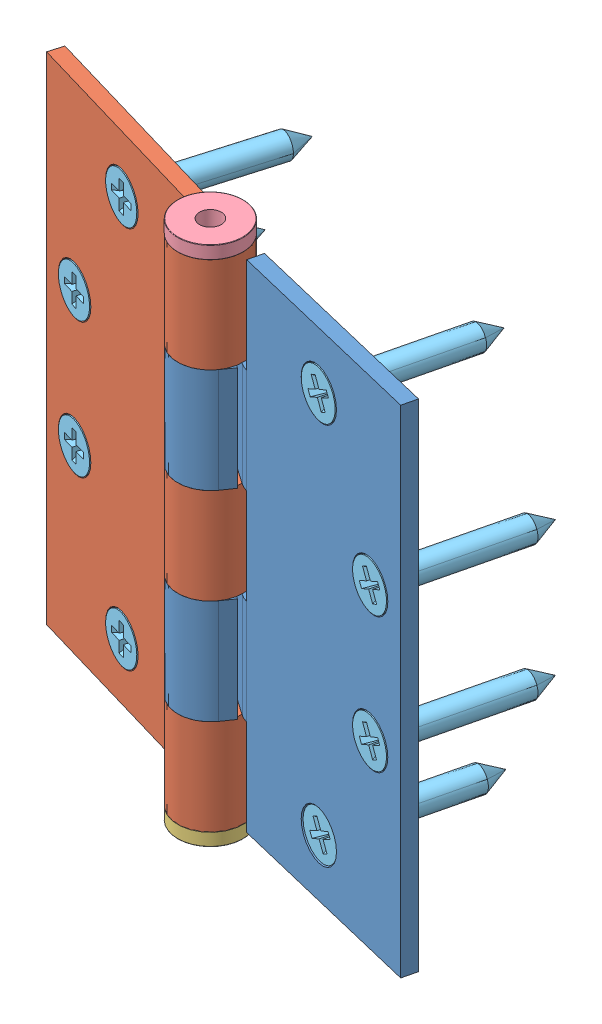
SolidWorks assembly socket pintu, configuration Default. Lengths in mm.
Overall size (119.47 119.8 70.68).
12 component instances, 5 part files, 46 mates.
Components (placement in the parent):
- Door Leaf-1: Door Leaf [Default] at (364.6395 -1637.4416 -365.5587) x (-0.972076 0 -0.234664) z (-0.234664 0 0.972076) size (65 114 15)
- Door right-3: Door right [Default] at (300.0571 -1637.4416 -382.8054) x (-0.959648 0 -0.281202) z (-0.281202 0 0.959648) size (65 114 15)
- Pin, Ball Bearing Door Hinge-1: Pin, Ball Bearing Door Hinge [Default] at (331.4179 -1694.3416 -370.6981) x (-1 0 0) z (0 0 1) size (15 110 15)
- Bottom Pin, Ball Bearing Door Hinge-1: Bottom Pin, Ball Bearing Door Hinge [Default] at (331.4179 -1577.5416 -370.6981) x (0.868974 0 -0.494857) z (-0.494857 0 -0.868974) size (15 9.5 15)
- M5.5 x 30, Wood Screw, Ball Bearing Door Hinge-1: M5.5 x 30, Wood Screw, Ball Bearing Door Hinge [Default] at (363.6317 -1681.4416 -367.7758) x (0.234664 0 -0.972076) z (0.849541 0.486025 0.205084) size (35.4 10.56 10.56)
- M5.5 x 30, Wood Screw, Ball Bearing Door Hinge-2: M5.5 x 30, Wood Screw, Ball Bearing Door Hinge [Default] at (286.5861 -1621.9416 -388.3979) x (0.281202 0 -0.959648) z (0.959648 0.000088 0.281202) size (35.4 10.56 10.56)
- M5.5 x 30, Wood Screw, Ball Bearing Door Hinge-3: M5.5 x 30, Wood Screw, Ball Bearing Door Hinge [Default] at (286.5861 -1652.9416 -388.3979) x (0.281202 0 -0.959648) z (0.959648 0.000088 0.281202) size (35.4 10.56 10.56)
- M5.5 x 30, Wood Screw, Ball Bearing Door Hinge-4: M5.5 x 30, Wood Screw, Ball Bearing Door Hinge [Default] at (301.9405 -1593.4416 -383.8986) x (0.281202 0 -0.959648) z (0.959648 0.000088 0.281202) size (35.4 10.56 10.56)
- M5.5 x 30, Wood Screw, Ball Bearing Door Hinge-5: M5.5 x 30, Wood Screw, Ball Bearing Door Hinge [Default] at (301.9405 -1681.4416 -383.8986) x (0.281202 0 -0.959648) z (0.959648 0.000088 0.281202) size (35.4 10.56 10.56)
- M5.5 x 30, Wood Screw, Ball Bearing Door Hinge-10: M5.5 x 30, Wood Screw, Ball Bearing Door Hinge [Default] at (379.1051 -1652.9416 -363.6907) x (0.234664 0 -0.972076) z (0.849541 0.486025 0.205084) size (35.4 10.56 10.56)
- M5.5 x 30, Wood Screw, Ball Bearing Door Hinge-11: M5.5 x 30, Wood Screw, Ball Bearing Door Hinge [Default] at (379.1051 -1621.9416 -363.6907) x (0.234664 0 -0.972076) z (0.849541 0.486025 0.205084) size (35.4 10.56 10.56)
- M5.5 x 30, Wood Screw, Ball Bearing Door Hinge-12: M5.5 x 30, Wood Screw, Ball Bearing Door Hinge [Default] at (363.5519 -1593.4416 -367.4453) x (0.234664 0 -0.972076) z (0.849541 0.486025 0.205084) size (35.4 10.56 10.56)
Mates (geometry in assembly coordinates):
- Concentric1: concentric anti-aligned: circle of Door Frame Leaf, Ball Bearing Door Hinge-3; circle of Pin, Ball Bearing Door Hinge-1
- Coincident1: coincident anti-aligned: circle of Door Frame Leaf, Ball Bearing Door Hinge-3; circle of Pin, Ball Bearing Door Hinge-1
- Coincident2: coincident aligned: circle of Door Leaf, Ball Bearing Door Hinge-1; circle of Door Frame Leaf, Ball Bearing Door Hinge-3
- Concentric4: concentric anti-aligned: circle of Door Frame Leaf, Ball Bearing Door Hinge-3; circle of Bottom Pin, Ball Bearing Door Hinge-1
- Coincident3: coincident aligned: circle of Door Frame Leaf, Ball Bearing Door Hinge-3; circle of Bottom Pin, Ball Bearing Door Hinge-1
- Concentric6: concentric aligned: circle of Door Leaf, Ball Bearing Door Hinge-1; circle of M5.5 x 30, Wood Screw, Ball Bearing Door Hinge-1
- Coincident4: coincident aligned: cone of Door Leaf, Ball Bearing Door Hinge-1 through (363.111 -1681.4416 -365.619) axis (0.234664 0 -0.972076); circle of M5.5 x 30, Wood Screw, Ball Bearing Door Hinge-1
- Coincident6: coincident aligned: cone of Door Frame Leaf, Ball Bearing Door Hinge-3 through (301.4122 -1681.4416 -382.0957) axis (0.281202 0 -0.959648); circle of M5.5 x 30, Wood Screw, Ball Bearing Door Hinge-5
- Coincident7: coincident aligned: cone of Door Frame Leaf, Ball Bearing Door Hinge-3 through (286.0578 -1652.9416 -386.5949) axis (0.281202 0 -0.959648); circle of M5.5 x 30, Wood Screw, Ball Bearing Door Hinge-3
- Coincident8: coincident aligned: cone of Door Frame Leaf, Ball Bearing Door Hinge-3 through (286.0578 -1621.9416 -386.5949) axis (0.281202 0 -0.959648); circle of M5.5 x 30, Wood Screw, Ball Bearing Door Hinge-2
- Coincident9: coincident aligned: cone of Door Frame Leaf, Ball Bearing Door Hinge-3 through (301.4122 -1593.4416 -382.0957) axis (0.281202 0 -0.959648); circle of M5.5 x 30, Wood Screw, Ball Bearing Door Hinge-4
- Coincident10: coincident aligned: cone of Door Leaf, Ball Bearing Door Hinge-1 through (378.6642 -1652.9416 -361.8644) axis (0.234664 0 -0.972076); circle of M5.5 x 30, Wood Screw, Ball Bearing Door Hinge-10
- Coincident11: coincident aligned: cone of Door Leaf, Ball Bearing Door Hinge-1 through (378.6642 -1621.9416 -361.8644) axis (0.234664 0 -0.972076); circle of M5.5 x 30, Wood Screw, Ball Bearing Door Hinge-11
- Coincident12: coincident aligned: cone of Door Leaf, Ball Bearing Door Hinge-1 through (363.111 -1593.4416 -365.619) axis (0.234664 0 -0.972076); circle of M5.5 x 30, Wood Screw, Ball Bearing Door Hinge-12
- Coincident13: coincident anti-aligned: circle of Pin, Ball Bearing Door Hinge-2; circle of Door Frame Leaf, Ball Bearing Door Hinge-4
- Concentric7: concentric anti-aligned: cylinder of Door Leaf, Ball Bearing Door Hinge-2; cylinder of Pin, Ball Bearing Door Hinge-2 through (331.4179 495.6584 -370.6981) axis (0 -1 0) radius 4
- Coincident14: coincident aligned: circle of Door Leaf, Ball Bearing Door Hinge-2; circle of Door Frame Leaf, Ball Bearing Door Hinge-4
- Coincident15: coincident aligned: cone of Door Frame Leaf, Ball Bearing Door Hinge-4 through (286.0578 464.0584 -386.5949) axis (0.281202 0 -0.959648); circle of M5.5 x 30, Wood Screw, Ball Bearing Door Hinge-20
- Coincident16: coincident aligned: circle of M5.5 x 30, Wood Screw, Ball Bearing Door Hinge-13; cone of Door Frame Leaf, Ball Bearing Door Hinge-4 through (286.0578 433.0584 -386.5949) axis (0.281202 0 -0.959648)
- Coincident17: coincident aligned: cone of Door Frame Leaf, Ball Bearing Door Hinge-4 through (301.4122 404.5584 -382.0957) axis (0.281202 0 -0.959648); circle of M5.5 x 30, Wood Screw, Ball Bearing Door Hinge-14
- Coincident18: coincident aligned: cone of Door Leaf, Ball Bearing Door Hinge-2 through (363.111 404.5584 -365.619) axis (0.234664 0 -0.972076); circle of M5.5 x 30, Wood Screw, Ball Bearing Door Hinge-18
- Coincident19: coincident aligned: cone of Door Leaf, Ball Bearing Door Hinge-2 through (378.6642 433.0584 -361.8644) axis (0.234664 0 -0.972076); circle of M5.5 x 30, Wood Screw, Ball Bearing Door Hinge-16
- Coincident20: coincident aligned: cone of Door Leaf, Ball Bearing Door Hinge-2 through (378.6642 464.0584 -361.8644) axis (0.234664 0 -0.972076); circle of M5.5 x 30, Wood Screw, Ball Bearing Door Hinge-15
- Coincident21: coincident aligned: cone of Door Leaf, Ball Bearing Door Hinge-2 through (363.111 492.5584 -365.619) axis (0.234664 0 -0.972076); circle of M5.5 x 30, Wood Screw, Ball Bearing Door Hinge-17
- Coincident22: coincident aligned: cone of Door Frame Leaf, Ball Bearing Door Hinge-4 through (301.4122 492.5584 -382.0957) axis (0.281202 0 -0.959648); circle of M5.5 x 30, Wood Screw, Ball Bearing Door Hinge-19
- Concentric9: concentric aligned: circle of Door Frame Leaf, Ball Bearing Door Hinge-4; cylinder of Bottom Pin, Ball Bearing Door Hinge-2 through (331.4179 508.5584 -370.6981) axis (0 1 0) radius 4.125
- Coincident24: coincident anti-aligned: plane of Door Frame Leaf, Ball Bearing Door Hinge-4; plane of Bottom Pin, Ball Bearing Door Hinge-2 through (323.9179 505.5584 -370.6981) normal (0 -1 0)
- Coincident46: coincident anti-aligned: plane of Door Leaf-1 through (365.0385 -1637.4416 -367.2112) normal (0.234664 0 -0.972076); plane of Part2-1 through (322.8176 559.7966 -377.4035) normal (-0.234664 0 0.972076)
- Coincident48: coincident aligned: line of Door Leaf-1 through (387.5704 -1694.4416 -358.2742) axis (0 1 0); line of Part2-1 through (387.5704 -1694.4416 -358.2742) axis (0 1 0)
- Coincident49: coincident: point of Door Leaf-1; moEndPointRef_w of Part2-1
- Coincident50: coincident: point of Door Leaf, Ball Bearing Door Hinge-2; point of Part2-1
- Coincident51: coincident: line of Door Leaf, Ball Bearing Door Hinge-2 through (340.9108 391.5584 -369.5381) axis (0.972076 0 0.234664); unknown of Part2-1
- Coincident60: coincident aligned: circle of khoa cua 4-1; plane of khoa cua 3-1 through (56.1694 626.2167 -190.1324) normal (0 1 0)
- Coincident64: coincident aligned: circle of khoa cua 4-1; circle of pp-1
- Concentric31: concentric anti-aligned: cylinder of khoa cua 3-1 through (229.0963 616.2167 -382.4309) axis (0 1 0) radius 2; cylinder of pp2-1 through (229.0963 612.7886 -382.4309) axis (0 -1 0) radius 2.5
- Coincident67: coincident anti-aligned: circle of khoa cua 3-1; circle of khoa cua 5-2
- Coincident68: coincident aligned: circle of khoa cua 5-2; circle of pp-2
- Coincident70: coincident anti-aligned: circle of khoa cua 5-2; circle of khoa cua 2-3
- Coincident73: coincident aligned: circle of khoa cua 2-3; circle of khoa cua-3
- Coincident147: coincident anti-aligned: plane of Part2-1 through (322.4891 559.7966 -376.0426) normal (-0.234664 0 0.972076); plane of khoa cua 4-1 through (213.3404 624.2167 -402.3917) normal (0.234664 0 -0.972076)
- Coincident148: coincident: line of Part2-1 through (205.5805 631.7164 -402.2075) axis (0 -1 0); unknown of khoa cua 4-1
- Coincident152: coincident anti-aligned: line of Part2-1 through (-940.2017 -669.4416 -698.351) axis (-0.972076 0 -0.234664); line of WemosD1-1 through (-1007.4306 -669.4416 -714.5804) axis (0.972076 0 0.234664)
- Coincident153: coincident anti-aligned: plane of Part2-1 through (326.4784 559.7966 -392.5679) normal (0.234664 0 -0.972076); plane of WemosD1-1 through (-974.7756 -642.6431 -706.6974) normal (-0.234664 0 0.972076)
- Coincident154: coincident: plane of Part2-1 through (-940.2017 -669.4416 -698.351) normal (-0.972076 0 -0.234664); line of WemosD1-1 through (-939.5914 -646.5806 -700.8794) axis (0 1 0)
- Coincident158: coincident anti-aligned: line of Part2-1 through (-970.0408 -544.9416 -788.8811) axis (0 1 0); line of ArduCAM MINI 2mp + ESP8266 Nano-2 through (-970.0408 -534.4416 -788.8811) axis (0 -1 0)
- Coincident159: coincident anti-aligned: line of Part2-1 through (-970.0408 -534.4416 -788.8811) axis (0.972076 0 0.234664); line of ArduCAM MINI 2mp + ESP8266 Nano-2 through (-959.834 -534.4416 -786.4171) axis (-0.972076 0 -0.234664)
